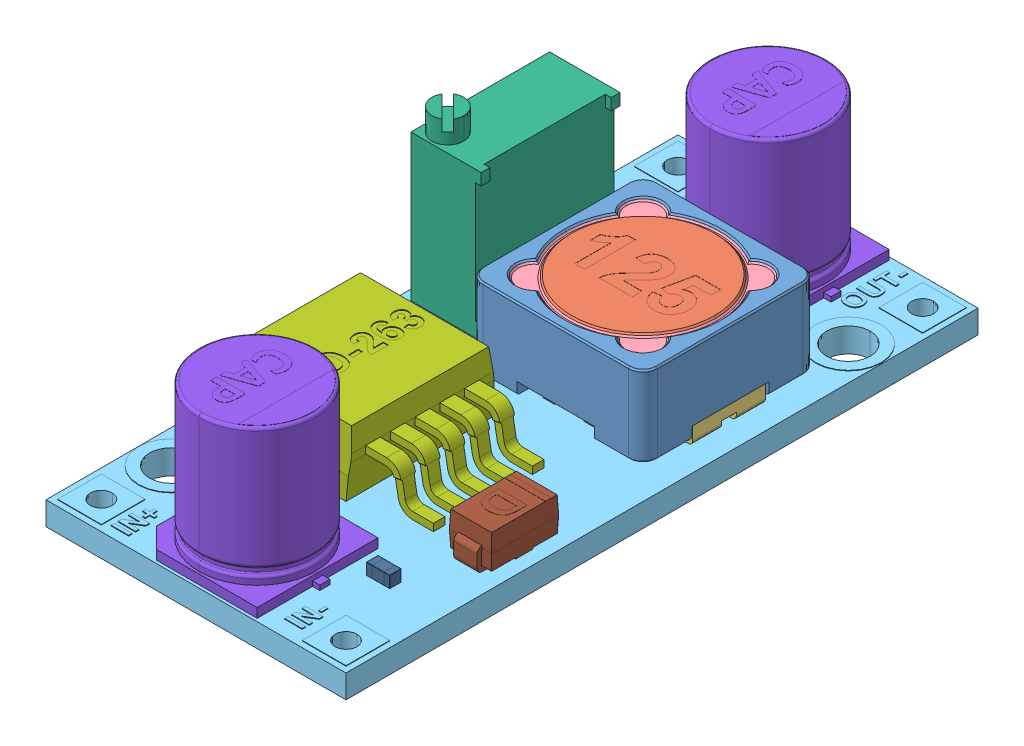
SolidWorks assembly DC_DC, configuration По умолчанию. Lengths in mm.
Overall size (20.6 13.97 43.4).
18 component instances, 12 part files, 0 mates.
Components (placement in the parent):
- HW-411.STEP-1: HW-411.STEP [По умолчанию] at origin size (20.6 13.97 43.4)
  - CDRH125^HW-411.STEP-1: CDRH125^HW-411.STEP [По умолчанию] at (13.1 2.1 -27.9) x (0 0 1) z (-1 0 0) size (12 6 12)
    - 001^CDRH125_HW-411.STEP-1: 001^CDRH125_HW-411.STEP [По умолчанию] at origin size (12 5.5 12)
    - 002^CDRH125_HW-411.STEP-1: 002^CDRH125_HW-411.STEP [По умолчанию] x (0 0 -1) z (1 0 0) size (10 5.5 10)
    - 005^CDRH125_HW-411.STEP-1: 005^CDRH125_HW-411.STEP [По умолчанию] at (0 -0.2 0) x (0 0 -1) z (1 0 0) size (4.9 2.2 10.12)
    - 005^CDRH125_HW-411.STEP-2: 005^CDRH125_HW-411.STEP [По умолчанию] at (0 -0.2 0) x (0 0 1) z (-1 0 0) size (4.9 2.2 10.12)
    - 003^CDRH125_HW-411.STEP-1: 003^CDRH125_HW-411.STEP [По умолчанию] at (0 4.9 0) size (10.6 0.5 10.6)
  - Board^HW-411.STEP-1: Board^HW-411.STEP [По умолчанию] at origin size (20.6 1.69 43.4)
  - RES_3296W^HW-411.STEP-1: RES_3296W^HW-411.STEP [По умолчанию] at (0.685 1.6 -33.9) x (0 0 1) z (-1 0 0) size (9.53 13.97 4.83)
  - TO-263-5^HW-411.STEP-1: TO-263-5^HW-411.STEP [По умолчанию] at (10.65 1.6 -15.2) x (0 0 -1) z (1 0 0) size (10 4.4 14.8)
  - CAP_SMD_AL_08.0x10.0^HW-411.STEP-1: CAP_SMD_AL_08.0x10.0^HW-411.STEP [По умолчанию] at (10.15 1.6 -4.35) x (0 0 1) z (-1 0 0) size (8.3 10.01 9.3)
  - CAP_SMD_AL_08.0x10.0^HW-411.STEP-2: CAP_SMD_AL_08.0x10.0^HW-411.STEP [По умолчанию] at (10.55 1.6 -39.05) x (0 0 1) z (-1 0 0) size (8.3 10.01 9.3)
  - RES_SMD_0603^HW-411.STEP-1: RES_SMD_0603^HW-411.STEP [По умолчанию] at (1 1.6 -22.25) size (1.6 0.38 0.85)
  - CAP_SMD_0603_H0.50^HW-411.STEP-1: CAP_SMD_0603_H0.50^HW-411.STEP [По умолчанию] at (4.6 1.6 -22.3) size (1.6 0.8 0.8)
  - CAP_SMD_0603_H0.50^HW-411.STEP-2: CAP_SMD_0603_H0.50^HW-411.STEP [По умолчанию] at (15.5 2.4 -7.3) x (1 0 0) z (0 0 -1) size (1.6 0.8 0.8)
  - Diode_DO214AC(SMA)^HW-411.STEP-1: Diode_DO214AC(SMA)^HW-411.STEP [По умолчанию] at (18.45 1.8 -13) x (-1 0 0) z (0 0 -1) size (2.9 2.61 5.3)
  - LED_0603_Green^HW-411.STEP-1: LED_0603_Green^HW-411.STEP [По умолчанию] at (1.6 1.6 -37.6) size (1.6 0.6 0.8)
  - RES_SMD_0603^HW-411.STEP-2: RES_SMD_0603^HW-411.STEP [По умолчанию] at (1.6 1.6 -35.25) size (1.6 0.38 0.85)
